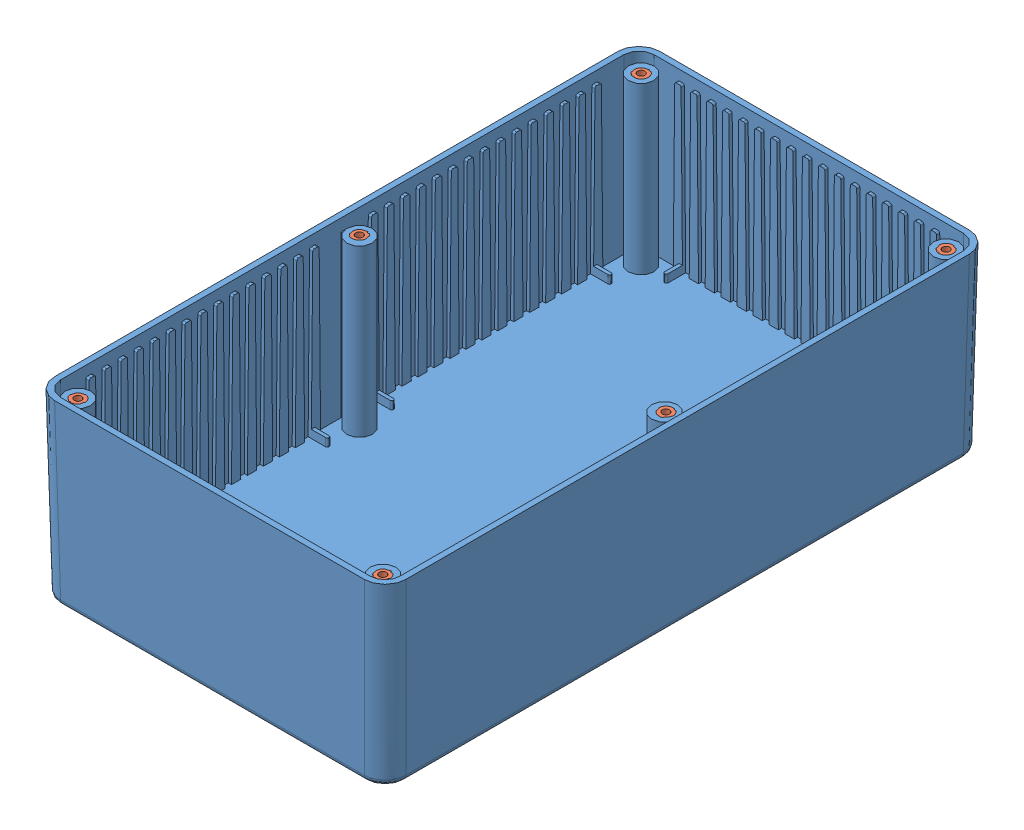
SolidWorks assembly bim2006_case_bottom, configuration Default. Lengths in mm.
Overall size (110 56 189.5).
7 component instances, 2 part files, 5 mates.
Components (placement in the parent):
- bim2006_case_bottom-1: bim2006_case_bottom [Default] at (-55 -56 94.75) size (110 56 189.5)
- insert-8: insert [Default] at (-55 -56 94.75) size (4.5 4.2 4.5)
- insert-9: insert [Default] at (-55 -56 -81.65) size (4.5 4.2 4.5)
- insert-10: insert [Default] at (40.5 -56 -81.65) size (4.5 4.2 4.5)
- insert-11: insert [Default] at (40.75 -56 6.3496) size (4.5 4.2 4.5)
- insert-12: insert [Default] at (-55.25 -56 6.3496) size (4.5 4.2 4.5)
- insert-13: insert [Default] at (40.5 -56 94.75) size (4.5 4.2 4.5)
Mates (geometry in assembly coordinates):
- Coincident1: coincident aligned: plane of bim2006_26_case_bottom-1 through (0 -56 94.75) normal (1 0 0)
- Coincident2: coincident aligned: plane of bim2006_26_case_bottom-1 through (-55 -56 0) normal (0 0 1)
- Coincident3: coincident aligned: plane of bim2006_26_case_bottom-1 through (-55 0 -94.75) normal (0 1 0)
- Concentric2: concentric aligned: cylinder of bim2006_26_case_bottom-1 through (-47.75 0 88.2) axis (0 1 0) radius 2.1; cylinder of insert-8 through (-47.75 -2.3 88.2) axis (0 1 0) radius 2.25
- Coincident5: coincident aligned: plane of bim2006_26_case_bottom-1 through (-55 -2.3 -94.75) normal (0 1 0); plane of insert-8 through (-47.75 -2.3 88.2) normal (0 1 0)
